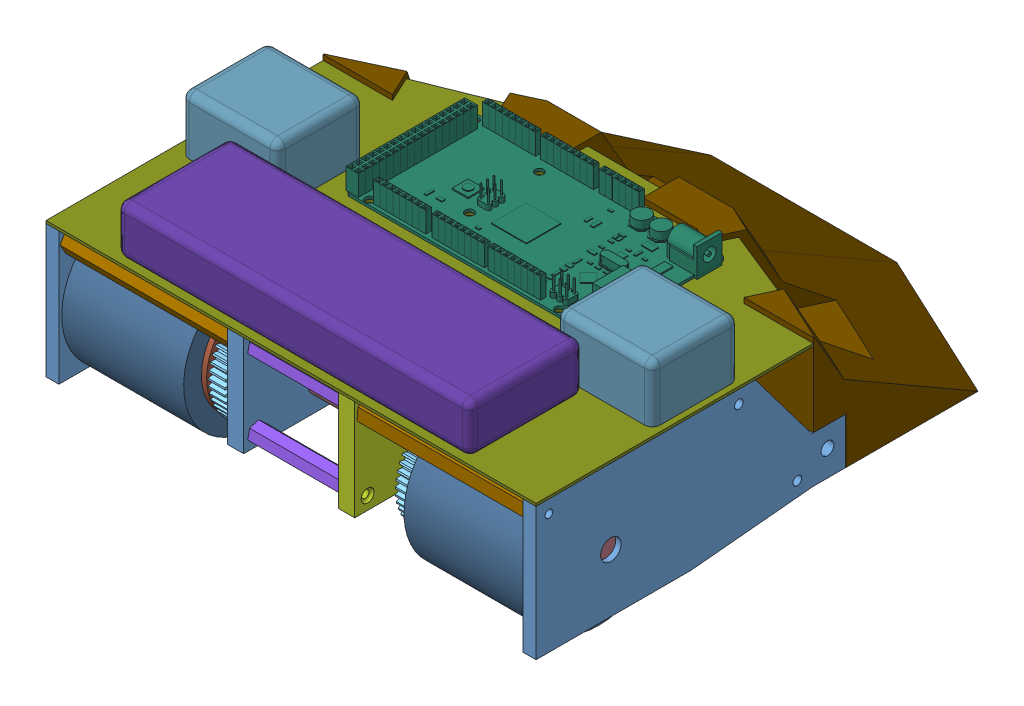
SolidWorks assembly Sumo 3.0, configuration Predeterminado. Lengths in mm.
Overall size (190.06 87.37 205.22).
56 component instances, 21 part files, 51 mates.
Components (placement in the parent):
- MotorMountIzquierdoAlvaro-1: MotorMountIzquierdoAlvaro [Predeterminado] at (118.6617 -17.2794 165.1113) x (0 0 1) z (-1 0 0) size (154.41 52.29 69.5)
  - B_Motor_Izquierda_Alvaro-1: B_Motor_Izquierda_Alvaro [Predeterminado] at (-34.1963 -12.2627 153.2797) size (154.41 47 6.35)
  - valero-1: valero [Predeterminado] at (18.135 -11.4835 154.6297) x (0.998644 0.052052 0) z (0 0 1) size (19 19 5)
  - CopleEngrane-1: CopleEngrane [Predeterminado] at (-31.5769 -5.0613 154.697) x (0 0 -1) z (0.99656 0.08288 0) size (30.68 43.16 43.16)
    - Cople-1: Cople [Predeterminado] at (4.4173 -10.5202 49.0087) x (0 0 -1) z (0 -1 0) size (34.5 28.68 34.5)
    - Gear 13T-1: Gear 13T [Default] at (-13.2577 -10.5202 49.0087) x (-1 0 0) z (0 0 -1) size (12 11.88 11.96)
    - Gear_52T-1: Gear_52T [Predeterminado] at (4.4173 -10.5202 49.0087) size (6.5 43.16 43.16)
  - MotorEngrane-1: MotorEngrane [Predeterminado] at (-13.0143 56.8165 177.6136) x (-1 0 0) z (0 -1 0) size (36 69.5 36)
    - Motor-1: Motor [Default] at (-5.1493 -20.5161 68.3) size (36 68.3 36)
    - Gear 13T-1: Gear 13T [Default] at (-5.1493 27.4839 68.3) x (0 1 0) z (-0.927124 0 -0.374755) size (12 11.88 11.96)
- MotorMountDerechoAlvaro-1: MotorMountDerechoAlvaro [Predeterminado] at (-150.9003 -17.5206 172.0871) x (0 0 -1) z (1 0 0) size (154.41 54 69.5)
  - B_Motor_Derecha_Alvaro-1: B_Motor_Derecha_Alvaro [Predeterminado] at (43.0754 -12.0207 159.3322) x (-1 0 0) z (0 0 -1) size (154.41 47 6.35)
  - CopleEngrane-1: CopleEngrane [Predeterminado] at (-61.2505 -9.4005 154.3995) x (0 0 -1) z (0.984779 0.173814 0) size (30.68 43.16 43.16)
    - Cople-1: Cople [Predeterminado] at (4.4173 -10.5202 49.0087) x (0 0 -1) z (0 -1 0) size (34.5 28.68 34.5)
    - Gear 13T-1: Gear 13T [Default] at (-13.2577 -10.5202 49.0087) x (-1 0 0) z (0 0 -1) size (12 11.88 11.96)
    - Gear_52T-1: Gear_52T [Predeterminado] at (4.4173 -10.5202 49.0087) size (6.5 43.16 43.16)
  - MotorEngrane-1: MotorEngrane [Predeterminado] at (19.9901 -79.5422 177.3161) x (1 0 0) z (0 1 0) size (36 69.5 36)
    - Motor-1: Motor [Default] at (-5.1493 -20.5161 68.3) size (36 68.3 36)
    - Gear 13T-1: Gear 13T [Default] at (-5.1493 27.4839 68.3) x (0 1 0) z (-0.927124 0 -0.374755) size (12 11.88 11.96)
  - valero-1: valero [Predeterminado] at (-11.1592 -11.2422 154.3322) x (0.98096 -0.194212 0) z (0 0 1) size (19 19 5)
- Postecorto-1: Postecorto [Predeterminado] at (-34.618 -4.7628 233.2463) x (0 0 -1) z (1 0 0) size (6.91 7.12 36.7)
- Postecorto-2: Postecorto [Predeterminado] at (-34.618 -4.7628 159.6226) x (0 0 -1) z (1 0 0) size (6.91 7.12 36.7)
- Postecorto-3: Postecorto [Predeterminado] at (-34.618 -41.7628 121.9449) x (0 0 -1) z (1 0 0) size (6.91 7.12 36.7)
- Postelargo-3: Postelargo [Predeterminado] at (8.432 -4.7628 159.6226) x (0 -0.204906 -0.978782) z (1 0 0) size (9.12 7.9 65.3)
- Postelargo-4: Postelargo [Predeterminado] at (-106.268 -4.7628 159.6226) x (0 0 -1) z (1 0 0) size (9.12 7.9 65.3)
- Postecorto-4: Postecorto [Predeterminado] at (-34.618 -33.7628 233.2463) x (0 0 -1) z (1 0 0) size (6.91 7.12 36.7)
- Postelargo-5: Postelargo [Predeterminado] at (-106.268 -4.7628 233.2463) x (0 0 -1) z (1 0 0) size (9.12 7.9 65.3)
- Postelargo-6: Postelargo [Predeterminado] at (8.432 -4.7628 233.2463) x (0 -0.996271 0.086284) z (1 0 0) size (9.12 7.9 65.3)
- Postecorto-5: Postecorto [Predeterminado] at (-34.618 -41.7628 136.9449) x (0 0 -1) z (1 0 0) size (6.91 7.12 36.7)
- Llanta-1: Llanta [Predeterminado] at (-5.593 -30.254 212.1226) x (0 -0.08023 -0.996776) z (1 0 0) size (59.21 59.21 57.2)
  - Latex-1: Latex [Predeterminado] at (2.7474 1.7171 32.05) size (55.8 55.8 47.5)
  - rine-1: rine [Predeterminado] at (2.7474 1.7171 30.05) x (0.649292 0.76054 0) z (0 0 1) size (42 42 57)
  - Gear_52T-1: Gear_52T [Predeterminado] at (2.7474 1.7171 28.85) x (0 0 -1) z (0.999983 -0.0058 0) size (6.5 43.16 43.16)
  - opresor-1: opresor [Predeterminado] at (2.7474 1.7171 22.55) size (15.9 15.9 6.35)
  - opresor-2: opresor [Predeterminado] at (2.7474 1.7171 73.2) size (15.9 15.9 6.35)
- Llanta-2: Llanta [Predeterminado] at (-26.943 -31.0396 206.9414) x (0 0.218876 0.975753) z (-1 0 0) size (59.21 59.21 57.2)
  - Latex-1: Latex [Predeterminado] at (2.7474 1.7171 32.05) size (55.8 55.8 47.5)
  - rine-1: rine [Predeterminado] at (2.7474 1.7171 30.05) x (0.649292 0.76054 0) z (0 0 1) size (42 42 57)
  - Gear_52T-1: Gear_52T [Predeterminado] at (2.7474 1.7171 28.85) x (0 0 -1) z (0.999983 -0.0058 0) size (6.5 43.16 43.16)
  - opresor-1: opresor [Predeterminado] at (2.7474 1.7171 22.55) size (15.9 15.9 6.35)
  - opresor-2: opresor [Predeterminado] at (2.7474 1.7171 73.2) size (15.9 15.9 6.35)
- eje-1: eje [Predeterminado] at (76.6324 -28.7628 209.2463) x (0 -0.992874 0.119169) z (0 -0.119169 -0.992874) size (8 186 8)
- Tapa_Conponents-1: Tapa_Conponents [Predeterminado] at (91.7554 32.7986 110.975) x (0 0 -1) z (1 0 0) size (130 23 190)
  - esc-1: esc [Predeterminado] at (-62.1642 -31.5615 -180.2195) x (0 0 -1) z (1 0 0) size (37.3 22 33.5)
  - esc-2: esc [Predeterminado] at (-63.1554 -31.5615 -33.9341) x (0 0 -1) z (1 0 0) size (37.3 22 33.5)
  - ArduinoMega-3: ArduinoMega [Predeterminado] at (-34.2591 -31.5615 -106.9891) x (0 0 1) z (-1 0 0) size (100 11.65 51.63)
  - base-2: base [Predeterminado] at (-62.2713 -31.5615 -108.0235) x (0 0 -1) z (0 -1 0) size (190 130 1)
  - NFC_shield-2: NFC_shield [Default] at (-34.4646 -35.2615 -95.9146) x (0 0 1) z (-1 0 0) size (116.84 18.41 53.34) (hidden)
  - PilaReal-1: PilaReal [Predeterminado] at (-103.7266 -31.5615 -108.6627) x (0 0 -1) z (0 1 0) size (137 44 19)
- Postelargo-7: Postelargo [Predeterminado] at (8.432 -41.7628 136.9449) x (0 0.975024 -0.222102) z (1 0 0) size (9.12 7.9 65.3)
- Postelargo-8: Postelargo [Predeterminado] at (-106.268 -41.7628 136.9449) x (0 -0.405842 -0.913943) z (1 0 0) size (9.12 7.9 65.3)
- Frente 3.0-1: Frente 3.0 [Predeterminado] at (-16.268 -46.7642 130.7641) size (190.06 50 91.37)
- Side3.0-1: Side3.0 [Predeterminado] at (73.732 -25.5128 178.2463) size (5 51.5 120)
- Side3.0-2: Side3.0 [Predeterminado] at (-111.268 -25.5128 178.2463) size (5 51.5 120)
- QTR-1RC-1: QTR-1RC [Predeterminado] at (65.5162 -45.2779 136.7641) x (1 0 0) z (0 0 -1) size (7.62 12.19 13.54)
- QTR-1RC-2: QTR-1RC [Predeterminado] at (-96.9452 -45.2779 136.7641) x (1 0 0) z (0 0 -1) size (7.62 12.19 13.54)
Mates (geometry in assembly coordinates):
- Concéntrica1: concentric: cylinder of MotorMountIzquierdoAlvaro-1/B_Motor_Izquierda_Alvaro-1 through (-40.968 -4.7628 233.2463) axis (1 0 0) radius 1.5; cylinder of MotorMountDerechoAlvaro-1/B_Motor_Derecha_Alvaro-1 through (2.082 -4.7628 233.2463) axis (1 0 0) radius 1.5
- Concéntrica2: concentric: cylinder of MotorMountIzquierdoAlvaro-1/B_Motor_Izquierda_Alvaro-1 through (-40.968 -41.7628 121.9449) axis (1 0 0) radius 1.5; cylinder of MotorMountDerechoAlvaro-1/B_Motor_Derecha_Alvaro-1 through (2.082 -41.7628 121.9449) axis (1 0 0) radius 1.5
- Concéntrica3: concentric: cylinder of MotorMountDerechoAlvaro-1/B_Motor_Derecha_Alvaro-1 through (2.082 -4.7628 233.2463) axis (1 0 0) radius 1.5; cylinder of Postecorto-1 through (-34.618 -4.7628 233.2463) axis (1 0 0) radius 1.7
- Coincidente1: coincident: plane of MotorMountIzquierdoAlvaro-1/B_Motor_Izquierda_Alvaro-1 through (-34.618 -29.5421 130.915) normal (1 0 0); plane of Postecorto-1 through (-34.618 -4.7628 233.2463) normal (-1 0 0)
- Coincidente2: coincident: plane of MotorMountDerechoAlvaro-1/B_Motor_Derecha_Alvaro-1 through (2.082 -29.5413 129.0118) normal (-1 0 0); plane of Postecorto-1 through (2.082 -4.7628 233.2463) normal (1 0 0)
- Concéntrica4: concentric: cylinder of MotorMountDerechoAlvaro-1/B_Motor_Derecha_Alvaro-1 through (2.082 -4.7628 159.6226) axis (1 0 0) radius 1.5; cylinder of Postecorto-2 through (-34.618 -4.7628 159.6226) axis (1 0 0) radius 1.7
- Coincidente6: coincident: plane of MotorMountDerechoAlvaro-1/B_Motor_Derecha_Alvaro-1 through (2.082 -29.5413 129.0118) normal (-1 0 0); plane of Postecorto-2 through (2.082 -4.7628 159.6226) normal (1 0 0)
- Concéntrica5: concentric: cylinder of MotorMountDerechoAlvaro-1/B_Motor_Derecha_Alvaro-1 through (2.082 -41.7628 121.9449) axis (1 0 0) radius 1.5; cylinder of Postecorto-3 through (-34.618 -41.7628 121.9449) axis (1 0 0) radius 1.7
- Coincidente7: coincident: plane of MotorMountIzquierdoAlvaro-1/B_Motor_Izquierda_Alvaro-1 through (-34.618 -29.5421 130.915) normal (1 0 0); plane of Postecorto-3 through (-34.618 -41.7628 121.9449) normal (-1 0 0)
- Concéntrica8: concentric: cylinder of MotorMountDerechoAlvaro-1/B_Motor_Derecha_Alvaro-1 through (2.082 -4.7628 159.6226) axis (1 0 0) radius 1.5; circle of Postelargo-3
- Coincidente9: coincident: plane of MotorMountDerechoAlvaro-1/B_Motor_Derecha_Alvaro-1 through (8.432 -29.5413 129.0118) normal (1 0 0); plane of Postelargo-3 through (8.432 -4.7628 159.6226) normal (-1 0 0)
- Concéntrica9: concentric: cylinder of MotorMountIzquierdoAlvaro-1/B_Motor_Izquierda_Alvaro-1 through (-40.968 -4.7628 159.6226) axis (1 0 0) radius 1.5; cylinder of Postelargo-4 through (-106.268 -4.7628 159.6226) axis (1 0 0) radius 1.7
- Coincidente10: coincident: plane of MotorMountIzquierdoAlvaro-1/B_Motor_Izquierda_Alvaro-1 through (-40.968 -29.5421 130.915) normal (-1 0 0); plane of Postelargo-4 through (-40.968 -4.7628 159.6226) normal (1 0 0)
- Concéntrica10: concentric: cylinder of MotorMountDerechoAlvaro-1/B_Motor_Derecha_Alvaro-1 through (2.082 -33.7628 233.2463) axis (1 0 0) radius 1.5; cylinder of Postecorto-4 through (-34.618 -33.7628 233.2463) axis (1 0 0) radius 1.7
- Coincidente11: coincident: plane of MotorMountIzquierdoAlvaro-1/B_Motor_Izquierda_Alvaro-1 through (-34.618 -29.5421 130.915) normal (1 0 0); plane of Postecorto-4 through (-34.618 -33.7628 233.2463) normal (-1 0 0)
- Concéntrica11: concentric: cylinder of MotorMountIzquierdoAlvaro-1/B_Motor_Izquierda_Alvaro-1 through (-40.968 -4.7628 233.2463) axis (1 0 0) radius 1.5; cylinder of Postelargo-5 through (-106.268 -4.7628 233.2463) axis (1 0 0) radius 1.7
- Concéntrica12: concentric: cylinder of MotorMountDerechoAlvaro-1/B_Motor_Derecha_Alvaro-1 through (2.082 -4.7628 233.2463) axis (1 0 0) radius 1.5; cylinder of Postelargo-6 through (8.432 -4.7628 233.2463) axis (1 0 0) radius 1.7
- Coincidente12: coincident: plane of MotorMountDerechoAlvaro-1/B_Motor_Derecha_Alvaro-1 through (8.432 -29.5413 129.0118) normal (1 0 0); plane of Postelargo-6 through (8.432 -4.7628 233.2463) normal (-1 0 0)
- Coincidente13: coincident: plane of MotorMountIzquierdoAlvaro-1/B_Motor_Izquierda_Alvaro-1 through (-40.968 -29.5421 130.915) normal (-1 0 0); plane of Postelargo-5 through (-40.968 -4.7628 233.2463) normal (1 0 0)
- Concéntrica13: concentric: cylinder of MotorMountDerechoAlvaro-1/B_Motor_Derecha_Alvaro-1 through (2.082 -41.7628 136.9449) axis (1 0 0) radius 1.5; cylinder of Postecorto-5 through (-34.618 -41.7628 136.9449) axis (1 0 0) radius 1.7
- Coincidente14: coincident: plane of MotorMountIzquierdoAlvaro-1/B_Motor_Izquierda_Alvaro-1 through (-34.618 -29.5421 130.915) normal (1 0 0); plane of Postecorto-5 through (-34.618 -41.7628 136.9449) normal (-1 0 0)
- Concéntrica14: concentric: cylinder of MotorMountIzquierdoAlvaro-1/B_Motor_Izquierda_Alvaro-1 through (-40.968 -28.7628 209.2463) axis (1 0 0) radius 3.95; cylinder of eje-1 through (-109.3676 -28.7628 209.2463) axis (1 0 0) radius 4
- Concéntrica16: concentric: cylinder of Llanta-2/opresor-1 through (-49.493 -28.7628 209.2463) axis (-1 0 0) radius 3.95; cylinder of eje-1 through (-109.3676 -28.7628 209.2463) axis (1 0 0) radius 4
- Concéntrica17: concentric: cylinder of Llanta-1/opresor-1 through (16.957 -28.7628 209.2463) axis (1 0 0) radius 3.95; cylinder of eje-1 through (-109.3676 -28.7628 209.2463) axis (1 0 0) radius 4
- Coincidente15: coincident: plane of MotorMountDerechoAlvaro-1/CopleEngrane-1/Gear 13T-1 through (16.757 -28.7628 183.2463) normal (-1 0 0); plane of Llanta-1/Gear_52T-1 through (16.757 -7.2429 207.3885) normal (-1 0 0)
- Coincidente16: coincident: plane of MotorMountIzquierdoAlvaro-1/CopleEngrane-1/Gear 13T-1 through (-49.293 -28.7628 183.2463) normal (1 0 0); plane of Llanta-2/Gear_52T-1 through (-49.293 -7.6595 204.6409) normal (1 0 0)
- Coincidente25: coincident: plane of MotorMountDerechoAlvaro-1/B_Motor_Derecha_Alvaro-1 through (2.082 0.2372 238.2463) normal (0 1 0); plane of Tapa_Conponents-1/base-2 through (-16.268 0.2372 173.2463) normal (0 -1 0)
- Concéntrica33: concentric: cylinder of MotorMountDerechoAlvaro-1/B_Motor_Derecha_Alvaro-1 through (2.082 -41.7628 136.9449) axis (1 0 0) radius 1.5; cylinder of Postelargo-7 through (8.432 -41.7628 136.9449) axis (1 0 0) radius 1.7
- Coincidente33: coincident: plane of MotorMountDerechoAlvaro-1/B_Motor_Derecha_Alvaro-1 through (8.432 -29.5413 129.0118) normal (1 0 0); plane of Postelargo-7 through (8.432 -41.7628 136.9449) normal (-1 0 0)
- Concéntrica34: concentric: cylinder of MotorMountIzquierdoAlvaro-1/B_Motor_Izquierda_Alvaro-1 through (-40.968 -41.7628 136.9449) axis (1 0 0) radius 1.5; cylinder of Postelargo-8 through (-106.268 -41.7628 136.9449) axis (1 0 0) radius 1.7
- Coincidente34: coincident: plane of MotorMountIzquierdoAlvaro-1/B_Motor_Izquierda_Alvaro-1 through (-40.968 -29.5421 130.915) normal (-1 0 0); plane of Postelargo-8 through (-40.968 -41.7628 136.9449) normal (1 0 0)
- Paralelo1: parallel: plane of MotorMountDerechoAlvaro-1/B_Motor_Derecha_Alvaro-1 through (2.081 -41.7628 83.8355) normal (0 -1 0); plane of Frente 3.0-1 through (8.432 -41.7628 83.8355) normal (0 1 0)
- Coincidente36: coincident: line of MotorMountDerechoAlvaro-1/B_Motor_Derecha_Alvaro-1 through (8.432 -28.8395 83.8355) axis (0 -1 0); line of Frente 3.0-1 through (8.432 -41.7628 83.8355) axis (0 1 0)
- Coincidente37: coincident: plane of MotorMountDerechoAlvaro-1/B_Motor_Derecha_Alvaro-1 through (2.081 -41.7628 83.8355) normal (0 -1 0); plane of Frente 3.0-1 through (8.432 -41.7628 83.8355) normal (0 1 0)
- Coincidente38: coincident: line of MotorMountIzquierdoAlvaro-1/B_Motor_Izquierda_Alvaro-1 through (-40.968 -28.8395 83.8355) axis (0 -1 0); line of Frente 3.0-1 through (-40.968 -28.8628 83.8355) axis (0 -1 0)
- Paralelo2: parallel: plane of MotorMountDerechoAlvaro-1/B_Motor_Derecha_Alvaro-1 through (8.432 -29.5413 129.0118) normal (1 0 0); plane of Side3.0-1 through (73.732 -25.5128 178.2463) normal (-1 0 0)
- Paralelo3: parallel: plane of MotorMountDerechoAlvaro-1/B_Motor_Derecha_Alvaro-1 through (2.082 0.2372 238.2463) normal (0 0 1); plane of Side3.0-1 through (78.732 -51.2628 238.2463) normal (0 0 1)
- Concéntrica35: concentric: cylinder of Postelargo-6 through (8.432 -4.7628 233.2463) axis (1 0 0) radius 1.7; cylinder of Side3.0-1 through (73.731 -4.7628 233.2463) axis (1 0 0) radius 1.5
- Concéntrica36: concentric: cylinder of eje-1 through (-109.3676 -28.7628 209.2463) axis (1 0 0) radius 4; cylinder of Side3.0-1 through (73.731 -28.7628 209.2463) axis (1 0 0) radius 4
- Coincidente43: coincident: plane of Postelargo-6 through (73.732 -4.7628 233.2463) normal (1 0 0); plane of Side3.0-1 through (73.732 -25.5128 178.2463) normal (-1 0 0)
- Concéntrica37: concentric: cylinder of eje-1 through (-109.3676 -28.7628 209.2463) axis (1 0 0) radius 4; cylinder of Side3.0-2 through (-111.269 -28.7628 209.2463) axis (1 0 0) radius 4
- Concéntrica38: concentric: cylinder of Postelargo-5 through (-106.268 -4.7628 233.2463) axis (1 0 0) radius 1.7; cylinder of Side3.0-2 through (-111.269 -4.7628 233.2463) axis (1 0 0) radius 1.5
- Concéntrica39: concentric: cylinder of Postelargo-8 through (-106.268 -41.7628 136.9449) axis (1 0 0) radius 1.7; cylinder of Side3.0-2 through (-106.267 -41.7628 136.9449) axis (-1 0 0) radius 1.7
- Coincidente45: coincident: plane of Postelargo-5 through (-106.268 -4.7628 233.2463) normal (-1 0 0); plane of Side3.0-2 through (-106.268 -25.5128 178.2463) normal (1 0 0)
- Coincidente47: coincident: plane of Tapa_Conponents-1/base-2 through (78.732 0.2372 238.2463) normal (0 0 1); plane of Side3.0-2 through (-106.268 -51.2628 238.2463) normal (0 0 1)
- Coincidente48: coincident: plane of Tapa_Conponents-1/base-2 through (78.732 0.2372 238.2463) normal (1 0 0); plane of Side3.0-1 through (78.732 -25.5128 178.2463) normal (1 0 0)
- Coincidente49: coincident: line of Frente 3.0-1 through (61.4627 -44.9642 117.2641) axis (1 0 0); line of QTR-1RC-1 through (61.4627 -44.9642 117.2641) axis (1 0 0)
- Coincidente50: coincident: plane of Frente 3.0-1 through (61.4627 -44.9642 117.2641) normal (1 0 0); plane of QTR-1RC-1 through (61.4627 -45.9642 130.2641) normal (-1 0 0)
- Coincidente51: coincident: line of Frente 3.0-1 through (-100.9988 -44.9642 117.2641) axis (1 0 0); line of QTR-1RC-2 through (-100.9988 -44.9642 117.2641) axis (1 0 0)
- Coincidente53: coincident: plane of Frente 3.0-1 through (-16.268 -44.9642 130.7641) normal (0 -1 0); plane of QTR-1RC-2 through (-97.4988 -44.9642 123.7641) normal (0 1 0)
- Coincidente54: coincident: plane of Frente 3.0-1 through (-93.9988 -44.9642 117.2641) normal (-1 0 0); plane of QTR-1RC-2 through (-93.9988 -45.9642 130.2641) normal (1 0 0)
